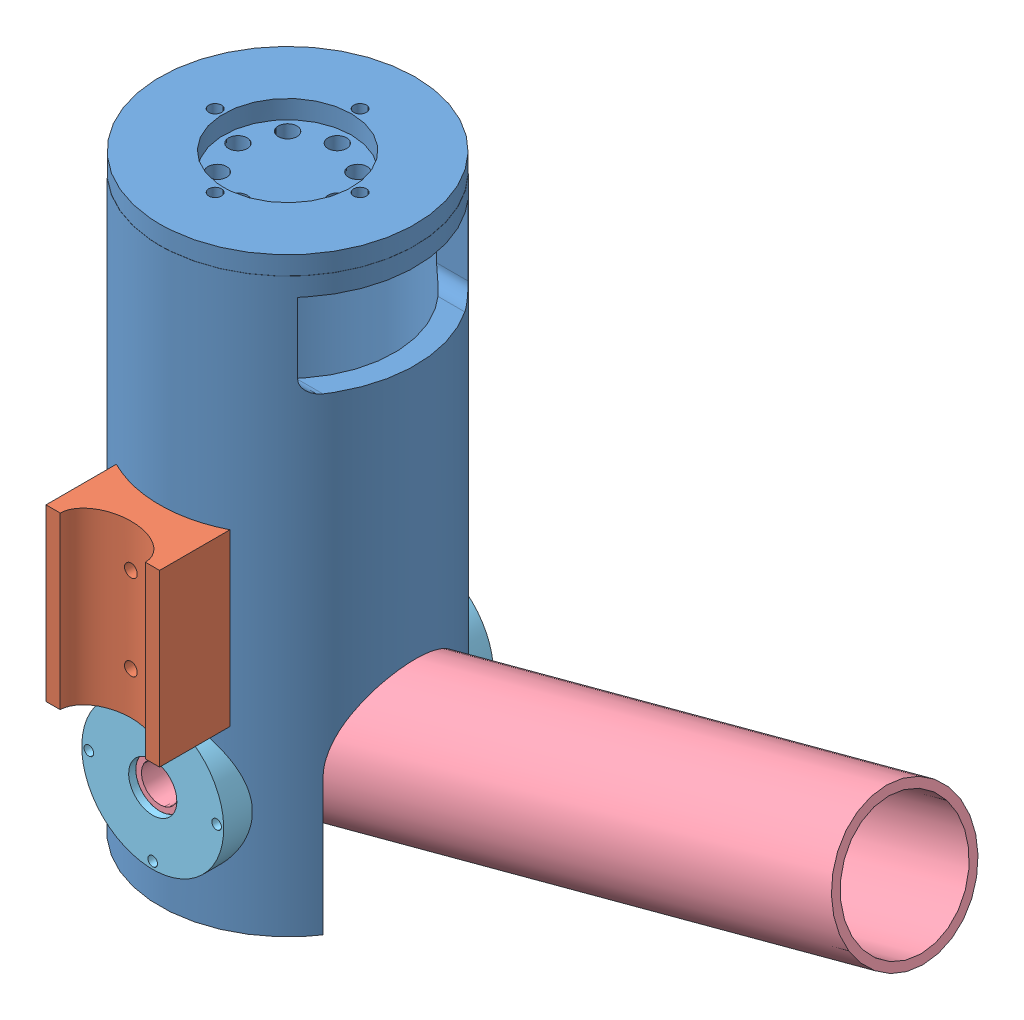
SolidWorks assembly Assem1, configuration Default. Lengths in mm.
Overall size (268.8 208 112.6).
7 component instances, 5 part files, 13 mates.
Components (placement in the parent):
- newArmShaft-1: newArmShaft [Default] at (-107.9767 245.207 253.6412) size (90 208 90)
- armmotormount-1: armmotormount [Default] at (-107.9767 112.707 254.5364) x (0 0 -1) z (1 0 0) size (24.78 60 40)
- 5972K104_BALL BEARING-2: 5972K104_BALL BEARING [5972K104] at (-107.9767 87.707 214.6412) size (40 40 12)
- 5972K104_BALL BEARING-3: 5972K104_BALL BEARING [5972K104] at (-107.9767 87.707 292.6412) size (40 40 12)
- 2nd arm section-2: 2nd arm section [Default] at (-132.1249 81.2365 253.6412) x (0 0 -1) z (0.258819 -0.965926 0) size (90 250 50)
- bearingsupport-1: bearingsupport [Default] at (-107.9767 87.707 301.1412) x (0 0 -1) z (0 1 0) size (11.74 50 50)
- bearingsupport-2: bearingsupport [Default] at (-107.9767 87.707 206.1412) x (0 0 1) z (0 -1 0) size (11.74 50 50)
Mates (geometry in assembly coordinates):
- Concentric6: concentric aligned: cylinder of newArmShaft-1 through (-107.9767 157.707 253.6412) axis (0 0 -1) radius 2.25; cylinder of armmotormount-1 through (-107.9767 157.707 254.5364) axis (0 0 -1) radius 2.25
- Coincident1: coincident: cylinder of newArmShaft-1 through (-107.9767 251.707 253.6412) axis (0 -1 0) radius 45; line of armmotormount-1 through (-127.9767 172.707 293.9525) axis (0 -1 0)
- Concentric9: concentric anti-aligned: cylinder of newArmShaft-1 through (-107.9767 87.707 304.6412) axis (0 0 -1) radius 20; cylinder of 5972K104_BALL BEARING-2 through (-107.9767 87.707 220.6412) axis (0 0 1) radius 20
- Concentric10: concentric anti-aligned: cylinder of newArmShaft-1 through (-107.9767 87.707 304.6412) axis (0 0 -1) radius 20; cylinder of 5972K104_BALL BEARING-3 through (-107.9767 87.707 298.6412) axis (0 0 1) radius 20
- Tangent4: tangent aligned: cylinder of newArmShaft-1 through (-107.9767 251.707 253.6412) axis (0 -1 0) radius 45; plane of 5972K104_BALL BEARING-3 through (-107.9767 107.107 298.6412) normal (0 0 1)
- Tangent5: tangent aligned: cylinder of newArmShaft-1 through (-107.9767 251.707 253.6412) axis (0 -1 0) radius 45; plane of 5972K104_BALL BEARING-2 through (-107.9767 107.107 208.6412) normal (0 0 -1)
- Concentric12: concentric anti-aligned: cylinder of 5972K104_BALL BEARING-3 through (-107.9767 87.707 298.6412) axis (0 0 1) radius 8.5; cylinder of 2nd arm section-2 through (-107.9767 87.707 298.6412) axis (0 0 -1) radius 8.5
- Coincident4: coincident aligned: plane of 5972K104_BALL BEARING-3 through (-107.9767 107.107 298.6412) normal (0 0 1); plane of 2nd arm section-2 through (-107.9767 87.707 298.6412) normal (0 0 1)
- Concentric13: concentric anti-aligned: cylinder of newArmShaft-1 through (-116.4234 85.4437 253.6412) axis (0.965926 0.258819 0) radius 25; cylinder of 2nd arm section-2 through (109.3566 145.9413 253.6412) axis (-0.965926 -0.258819 0) radius 25
- Concentric14: concentric anti-aligned: cylinder of 5972K104_BALL BEARING-3 through (-107.9767 87.707 298.6412) axis (0 0 1) radius 20; cylinder of bearingsupport-1 through (-107.9767 87.707 298.6412) axis (0 0 -1) radius 20
- Concentric15: concentric aligned: cylinder of newArmShaft-1 through (-107.9767 251.707 253.6412) axis (0 -1 0) radius 45; cylinder of bearingsupport-1 through (-107.9767 116.707 253.6412) axis (0 -1 0) radius 45
- Concentric16: concentric aligned: cylinder of 5972K104_BALL BEARING-2 through (-107.9767 87.707 220.6412) axis (0 0 1) radius 20; cylinder of bearingsupport-2 through (-110.7648 85.7669 199.3969) axis (0 0 1) radius 20
- Concentric17: concentric anti-aligned: cylinder of newArmShaft-1 through (-107.9767 251.707 253.6412) axis (0 -1 0) radius 45; cylinder of bearingsupport-2 through (-107.9767 58.707 253.6412) axis (0 1 0) radius 45
